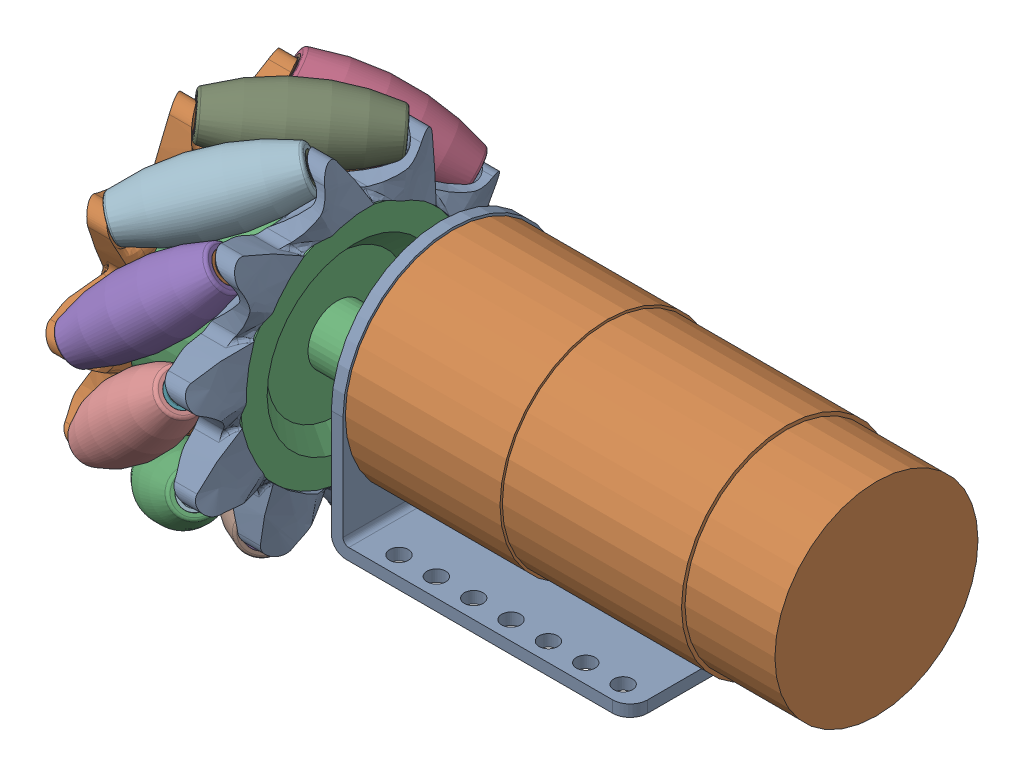
SolidWorks assembly MecanumWMotor, configuration Default. Lengths in mm.
Overall size (118.9 78.93 78.86).
3 component instances, 3 part files, 5 mates.
Components (placement in the parent):
- 37D bracket -1: 37D bracket  [Default] at origin size (51.2 39.6 37.6)
- Motor - 37D - with encoder - 100_1 and 131_1-1: Motor - 37D - with encoder - 100_1 and 131_1 [Default] at (74.6 20.8 0) x (0 0 1) z (-1 0 0) size (36.8 36.8 94.6)
- Mecanum Wheel Right-1: Mecanum Wheel Right [Default] at (-8.3271 45.8337 -42.2568) x (1 0 0) z (0 -0.351292 0.936266) size (34.3 61.34 61.21)
Mates (geometry in assembly coordinates):
- Concentric1: concentric: cylinder of 37D bracket -1 through (51.201 13.8 0) axis (-1 0 0) radius 6.6; cylinder of Motor - 37D - with encoder - 100_1 and 131_1-1 through (-4.5 13.8 0) axis (1 0 0) radius 6
- Coincident1: coincident: plane of 37D bracket -1 through (2 3 18.8) normal (1 0 0); plane of Motor - 37D - with encoder - 100_1 and 131_1-1 through (2 20.8 0) normal (-1 0 0)
- Concentric2: concentric aligned: cylinder of 37D bracket -1 through (51.201 34.2234 -7.75) axis (-1 0 0) radius 1.2044; cylinder of Motor - 37D - with encoder - 100_1 and 131_1-1 through (2 34.2234 -7.75) axis (-1 0 0) radius 1.25
- Concentric3: concentric: cylinder of Motor - 37D - with encoder - 100_1 and 131_1-1 through (-20 13.8 0) axis (1 0 0) radius 3; cylinder of Mecanum Wheel Right-1 through (-39.7152 13.8 0) axis (1 0 0) radius 2.7
- Coincident2: coincident anti-aligned: plane of Motor - 37D - with encoder - 100_1 and 131_1-1 through (-20 13.8 0) normal (-1 0 0); plane of Mecanum Wheel Right-1 through (-20 13.8 0) normal (1 0 0)
